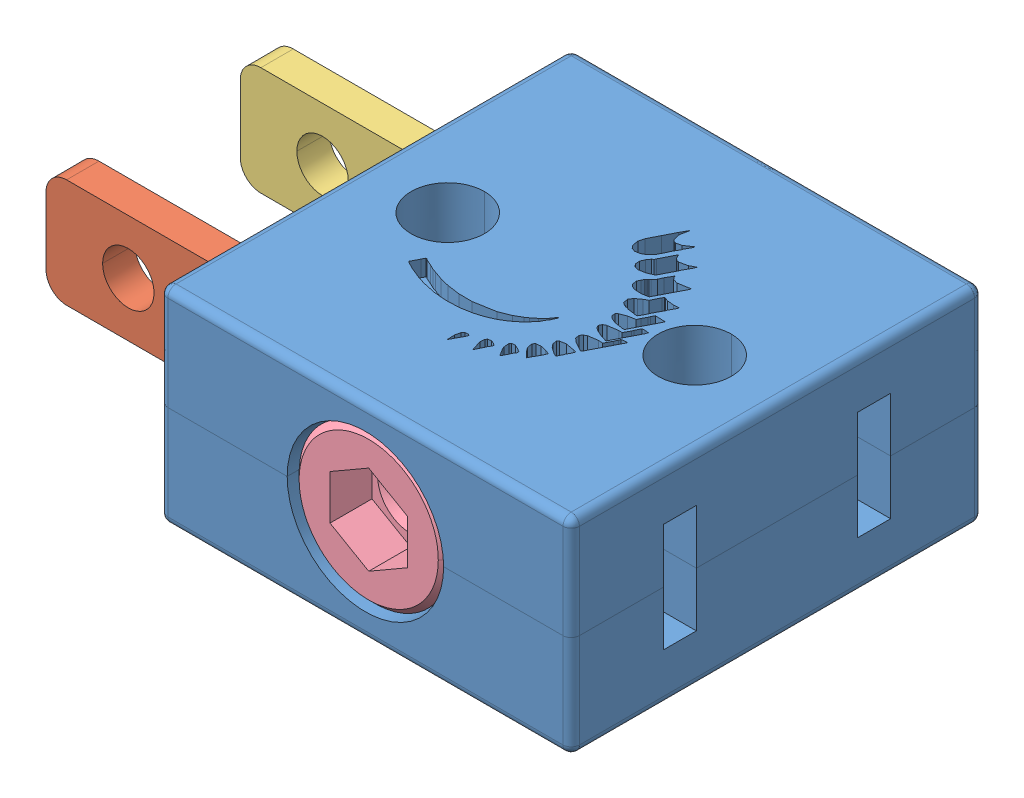
SolidWorks assembly Fingertech_Switch, configuration Default. Lengths in mm.
Overall size (19.06 6.61 12.71).
6 component instances, 4 part files, 0 mates.
Components (placement in the parent):
- Mini_Power_Switch.IGS-1: Mini_Power_Switch.IGS [Default] at origin size (19.06 6.61 12.71)
  - switch half R1.1.IGS-1: switch half R1.1.IGS [Default] at (-0.0319 -2.7572 1.89) size (12.72 4.51 12.71)
  - switch half R1.1.IGS-2: switch half R1.1.IGS [Default] at (-0.0319 3.5928 1.89) x (-1 0 0) z (0 0 1) size (12.72 4.51 12.71)
  - copper tab_through hole.IGS-1: copper tab_through hole.IGS [Default] at (-4.4769 0.4178 4.3948) size (16.52 4.58 1.01)
  - copper tab.IGS-1: copper tab.IGS [Default] at (-4.4769 0.4178 -1.5988) size (16.52 4.58 1.01)
  - SHCS 4-40x375_HX-SHCS 0.112-40x0.375x0.375-S.IGS-1: SHCS 4-40x375_HX-SHCS 0.112-40x0.375x0.375-S.IGS [Default] at (-0.0319 0.4178 8.138) x (0 0 -1) z (1 0 0) size (12.09 6.61 4.66)
